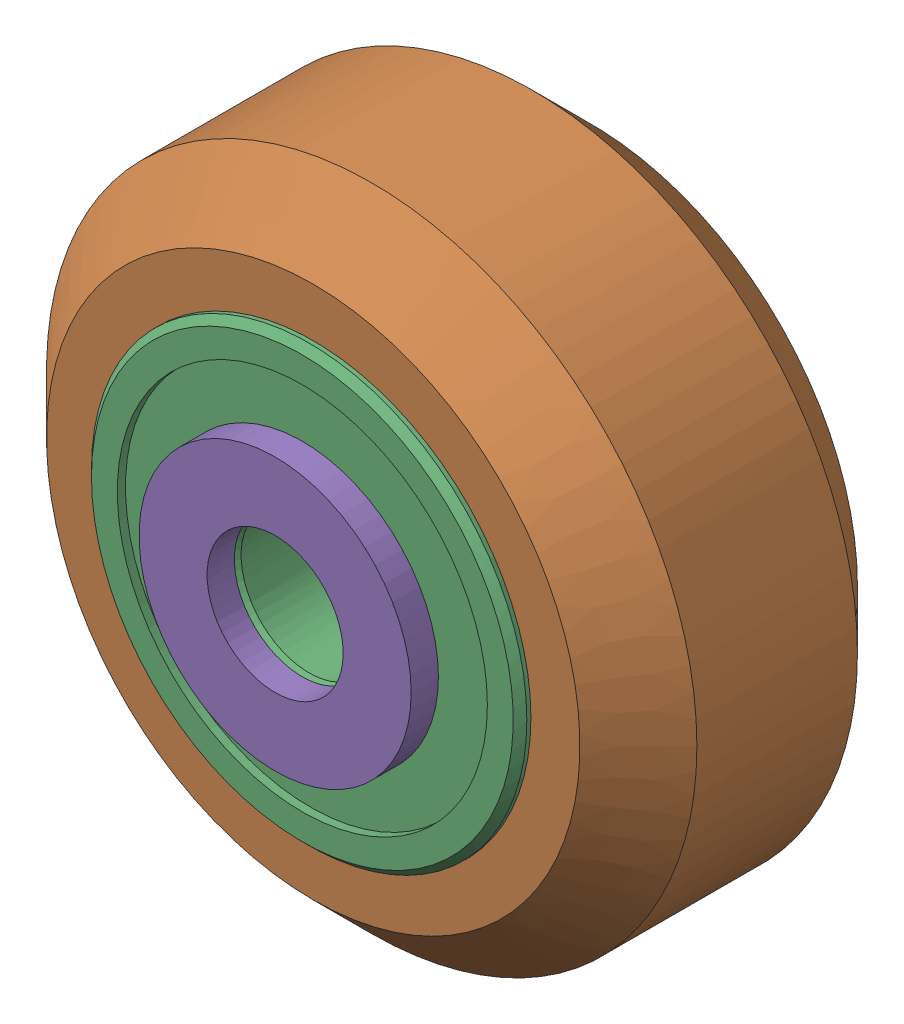
SolidWorks assembly Xtreme Solid V Wheel Kit Assembly_1, configuration Default. Lengths in mm.
Overall size (23.9 23.9 13).
6 component instances, 3 part files, 0 mates.
Components (placement in the parent):
- Precision Shim - 10x5x1mm-1: Precision Shim - 10x5x1mm [Default] at origin size (10 10 1)
- Xtreme Solid V Wheel Assembly_1-1: Xtreme Solid V Wheel Assembly_1 [Default] at (45.15 55 -23.5) size (23.9 23.9 11)
  - Xtreme Solid V Wheel-1: Xtreme Solid V Wheel [Default] at (-45.15 -55 30) x (0 0 1) z (-1 0 0) size (10.2 23.9 23.9)
  - Wheel+Kit+-+5x16x5mm+Sealed+Radial+Ball+Bearing.step.f3d-1: Wheel+Kit+-+5x16x5mm+Sealed+Radial+Ball+Bearing.step.f3d [Default] at (-45.15 -55 30) x (0 1 0) z (-1 0 0) size (16 5 16)
  - Wheel+Kit+-+5x16x5mm+Sealed+Radial+Ball+Bearing.step.f3d-2: Wheel+Kit+-+5x16x5mm+Sealed+Radial+Ball+Bearing.step.f3d [Default] at (-45.15 -55 30) x (0 1 0) z (1 0 0) size (16 5 16)
- Precision Shim - 10x5x1mm-2: Precision Shim - 10x5x1mm [Default] at (0 0 12) size (10 10 1)
